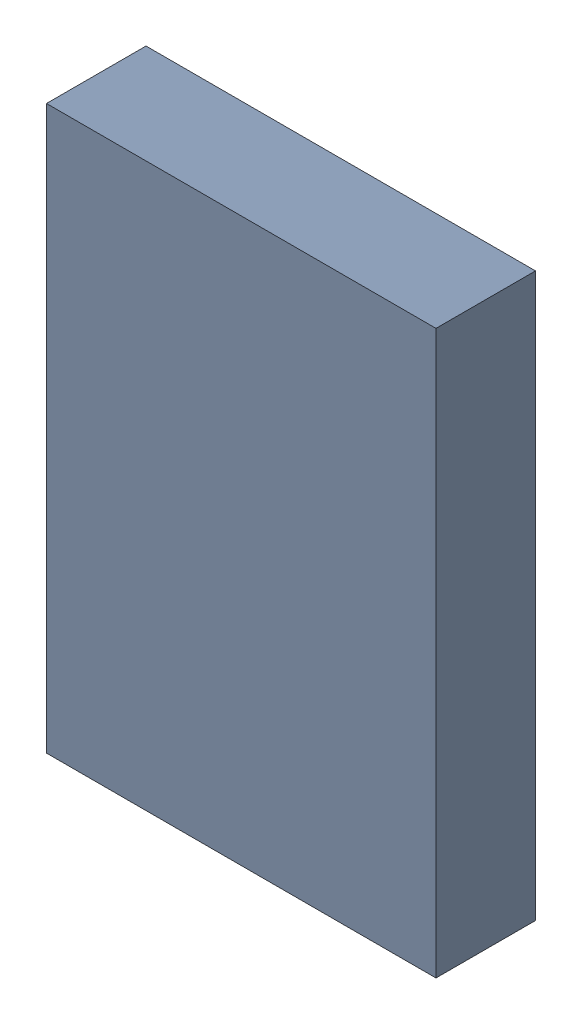
SolidWorks assembly U3Kanaloa_v2.0.0_Motor, configuration Default. Lengths in mm.
Overall size (4.5 6.5 1.15).
2 component instances, 1 part files, 0 mates.
Components (placement in the parent):
- 334789680-1: 334789680 [Default] at (125.222 114.554 0) size (4.5 6.5 1.15)
  - Extruded_17-1: Extruded_17 [Default] at origin size (4.5 6.5 1.15)
